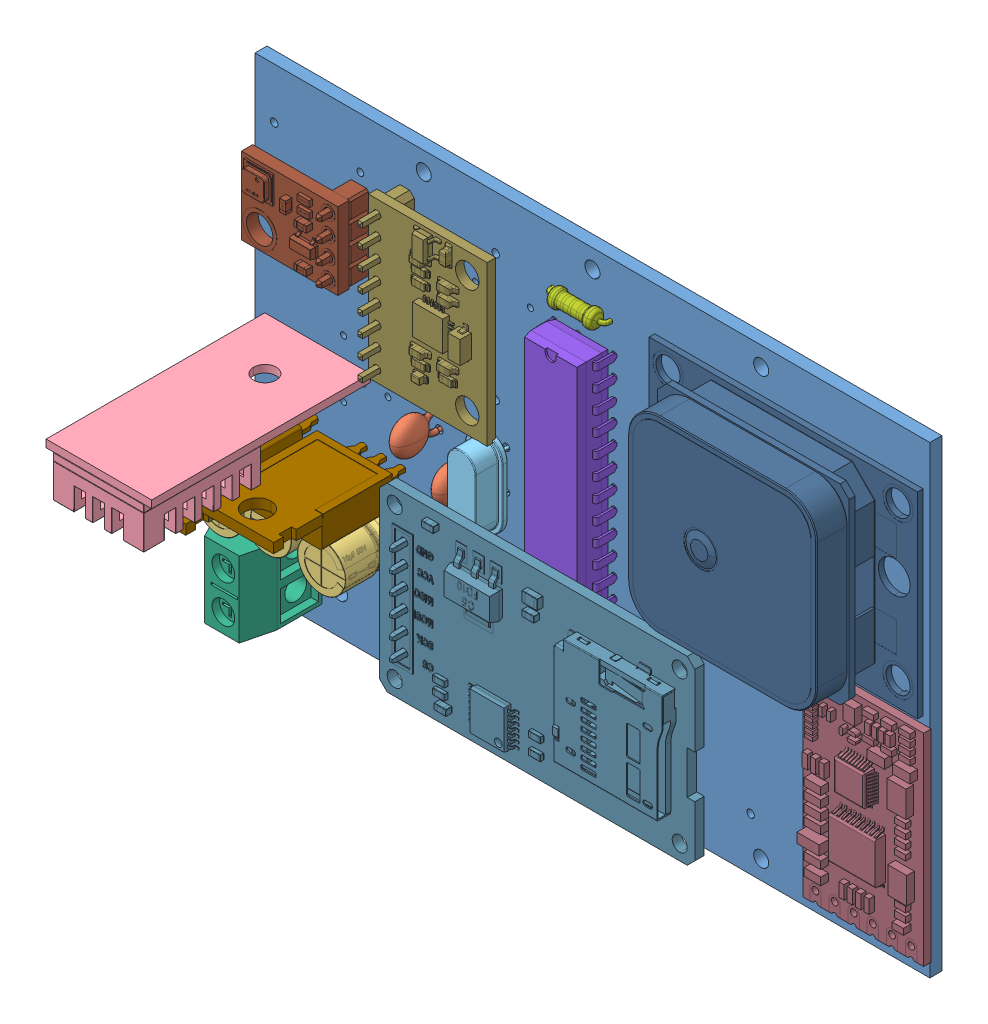
SolidWorks assembly OBTIMIZED printing.step, configuration Default. Lengths in mm.
Overall size (93.91 61.5 56.19).
18 component instances, 14 part files, 0 mates.
Components (placement in the parent):
- Board_OBTIMIZED_printing.step-1: Board_OBTIMIZED_printing.step [Default] at origin size (89.5 61.5 1.59)
- 10pF_Ceramic_Disc_3.step-1: 10pF_Ceramic_Disc_3.step [Default] at (24.4475 31.75 4) x (0 -1 0) z (-1 0 0) size (9.4 30.04 2.5)
- 10pF_Ceramic_Disc_3.step-2: 10pF_Ceramic_Disc_3.step [Default] at (30.0037 29.0513 4) x (-0.000018 1 0) z (1 0.000018 0) size (9.4 30.04 2.5)
- CAP_10uF_50V_low_profile.step-1: CAP_10uF_50V_low_profile.step [Default] at (4.1275 15.8755 2) x (-1 0 0) z (0 1 0) size (11.58 15.96 10.81)
- CAP_10uF_50V_low_profile.step-2: CAP_10uF_50V_low_profile.step [Default] at (10.6362 16.8275 2) x (0 1 0) z (1 0 0) size (11.58 15.96 10.81)
- CAP_10uF_50V_low_profile.step-3: CAP_10uF_50V_low_profile.step [Default] at (17.78 15.8755 2) x (1 0 0) z (0 -1 0) size (11.58 15.96 10.81)
- DHT11_module.step-1: DHT11_module.step [Default] at (5.7475 34.75 17) x (1 0 0) z (0 -1 0) size (14.01 35.06 6.51)
- Crystal_Oscillator.step-1: Crystal_Oscillator.step [Default] at (33.3375 30.3213 6) x (0.00004 -1 0) z (-1 -0.00004 0) size (11.5 16.83 5)
- Terminal_block_5mm.step-1: Terminal_block_5mm.step [Default] at (8.8975 2.665 0) x (0 1 0) z (0 0 1) size (10.61 7.61 15.04)
- Resistor_10K_Ohm_tol1pct_0,25W__07,62.step-1: Resistor_10K_Ohm_tol1pct_0,25W__07,62.step [Default] at (43.3387 54.2925 0.8) x (-0.000037 1 0) z (0 0 1) size (2.86 8.18 5.93)
- ATMEGA328P-PU.step-1: ATMEGA328P-PU.step [Default] at (43.6563 34.1313 0.05) x (0 -1 0) z (0 0 1) size (34.8 8.22 6.57)
- TO220.step-1: TO220.step [Default] at (1.3975 20.995 13) x (-1 0 0) z (0 0 -1) size (10 4.55 28.74)
- TO220.step-2: TO220.step [Default] at (20.9862 25.9951 13) x (1 0.000029 0) z (0 0 -1) size (10 4.55 28.74)
- A_GPS_main.step-1: A_GPS_main.step [Default] at (72.2613 65.2625 0) x (-1 0 0) z (0 -1 0) size (35.61 12.34 26.09)
- BMP180_Breakout.step-1: BMP180_Breakout.step [Default] at (8.7945 48.4236 4.2) x (1 0.000033 0) z (0 0 -1) size (12.81 10.21 11.95)
- MPU6050.step-1: MPU6050.step [Default] at (10.0637 38.7362 -7.8) x (0 1 0) z (1 0 0) size (21.12 11.19 15.89)
- Dorji_RfModule(DRF4432D20I).step-1: Dorji_RfModule(DRF4432D20I).step [Default] at (89.6713 1.8988 0) x (0 1 0) z (0 0 1) size (26.8 16 2.4)
- Product_TF_Micro_SD_Card_Memory_Modul_Arduino.step-1: Product_TF_Micro_SD_Card_Memory_Modul_Arduino.step [Default] at (66.5725 17.1025 7) x (0 1 0) z (0 0 1) size (24.01 41.81 11.47)
